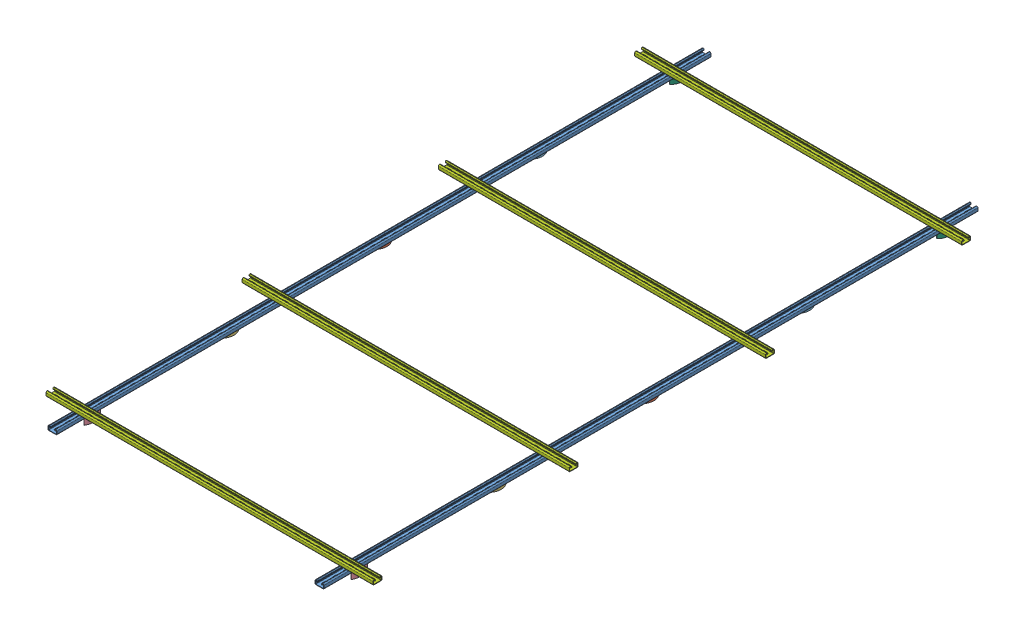
SolidWorks assembly Roof Rack Assembly, configuration Default. Lengths in mm.
Overall size (1524 88.07 3048).
18 component instances, 7 part files, 5 mates.
Components (placement in the parent):
- Roof Rack Strut-1: Roof Rack Strut [Default] at (0 -1893.0006 566.2194) size (41.28 67.43 3048)
  - 3310T8_Strut Channel-1: 3310T8_Strut Channel [3310T8] at (-622.3 1893.0006 957.7806) x (0 -1 0) z (0 0 1) size (20.64 41.27 3048)
  - Center Spacer V1-1: Center Spacer V1 [Default] at (-622.3 1880.3006 -584.4756) size (31.75 16.33 76.2)
  - Front Center Spacer V1-1: Front Center Spacer V1 [Default] at (-622.3 1878.7131 126.7244) size (31.75 18.31 76.2)
  - Front Spacer V1-1: Front Spacer V1 [Default] at (-622.3 1854.9006 772.8369) size (31.75 46.79 76.2)
  - Rear Center Spacer V1-1: Rear Center Spacer V1 [Default] at (-622.3 1881.8881 -1309.9631) size (31.75 14.47 76.2)
  - Rear Spacer V1-1: Rear Spacer V1 [Default] at (-622.3 1858.0756 -1956.0756) size (31.75 40.44 76.2)
- Roof Rack Strut-3: Roof Rack Strut [Default] at (1244.6 -1893.0006 566.2194) size (41.28 67.43 3048)
  - 3310T8_Strut Channel-1: 3310T8_Strut Channel [3310T8] at (-622.3 1893.0006 957.7806) x (0 -1 0) z (0 0 1) size (20.64 41.27 3048)
  - Center Spacer V1-1: Center Spacer V1 [Default] at (-622.3 1880.3006 -584.4756) size (31.75 16.33 76.2)
  - Front Center Spacer V1-1: Front Center Spacer V1 [Default] at (-622.3 1878.7131 126.7244) size (31.75 18.31 76.2)
  - Front Spacer V1-1: Front Spacer V1 [Default] at (-622.3 1854.9006 772.8369) size (31.75 46.79 76.2)
  - Rear Center Spacer V1-1: Rear Center Spacer V1 [Default] at (-622.3 1881.8881 -1309.9631) size (31.75 14.47 76.2)
  - Rear Spacer V1-1: Rear Spacer V1 [Default] at (-622.3 1858.0756 -1956.0756) size (31.75 40.44 76.2)
- 3310T49_Strut Channel-1: 3310T49_Strut Channel [3310T49] at (762 20.6375 -1349.6443) x (0 -1 0) z (1 0 0) size (20.64 41.27 1524)
- 3310T49_Strut Channel-2: 3310T49_Strut Channel [3310T49] at (762 20.6375 -435.2443) x (0 -1 0) z (1 0 0) size (20.64 41.27 1524)
- 3310T49_Strut Channel-3: 3310T49_Strut Channel [3310T49] at (762 20.6375 479.1557) x (0 -1 0) z (1 0 0) size (20.64 41.27 1524)
- 3310T49_Strut Channel-4: 3310T49_Strut Channel [3310T49] at (762 20.6375 1393.5557) x (0 -1 0) z (1 0 0) size (20.64 41.27 1524)
Mates (geometry in assembly coordinates):
- Coincident12: coincident anti-aligned: plane of Roof Rack Strut-1/3310T8_Strut Channel-1 through (-606.7107 20.6375 -1524) normal (0 1 0); plane of 3310T49_Strut Channel-1 through (-762 20.6375 -1366.821) normal (0 -1 0)
- Coincident13: coincident aligned: plane of 3310T49_Strut Channel-1 through (0 20.6375 -1349.6443) normal (1 0 0)
- Coincident14: coincident aligned: plane of Roof Rack Strut-1/3310T8_Strut Channel-1 through (-622.3 0 0) normal (0 0 1)
- Coincident15: coincident anti-aligned: plane of Roof Rack Strut-1/3310T8_Strut Channel-1 through (-605.1232 0 -1524) normal (0 -1 0)
- Distance1: distance = 622.3 mm aligned: plane of Roof Rack Strut-1/3310T8_Strut Channel-1 through (-622.3 0 1524) normal (1 0 0)
